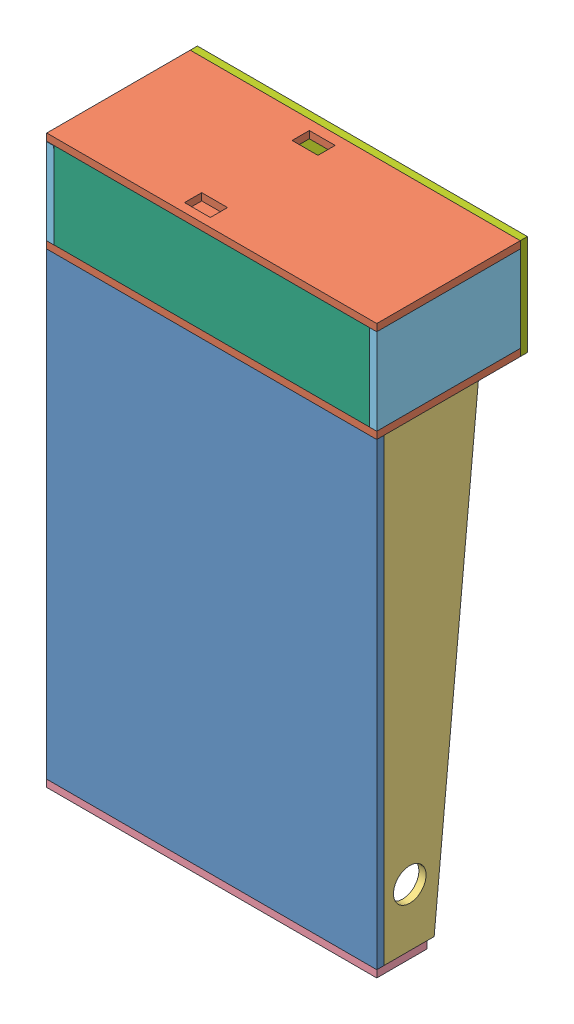
SolidWorks assembly pinball enclosure, configuration Default. Lengths in mm.
Overall size (292.1 501.65 133.49).
10 component instances, 7 part files, 20 mates.
Components (placement in the parent):
- base-1: base [Default] at (-22.2042 13.1183 317.2401) size (292.1 406.4 6.35)
- backboard-1: backboard [Default] at (-22.2042 425.8683 196.5901) x (1 0 0) z (0 -1 0) size (292.1 127 6.35)
- side panel-1: side panel [Default] at (263.5458 419.5183 317.2401) x (0 -1 0) z (1 0 0) size (406.4 83.57 6.35)
- side panel-2: side panel [Default] at (-22.2042 419.5183 317.2401) x (0 -1 0) z (1 0 0) size (406.4 83.57 6.35)
- front panel-1: front panel [Default] at (-22.2042 6.7683 323.5901) x (1 0 0) z (0 1 0) size (292.1 57.15 6.35)
- backboard side panel-1: backboard side panel [Default] at (263.5458 502.0683 323.5901) x (0 -1 0) z (1 0 0) size (76.2 127 6.35)
- backboard base-1: backboard base [Default] at (-15.8542 425.8683 317.2401) size (279.4 76.2 6.35)
- backboard-2: backboard [Default] at (-22.2042 508.4183 196.5901) x (1 0 0) z (0 -1 0) size (292.1 127 6.35)
- backboard top-1: backboard top [Default] at (-22.2042 419.5183 190.2401) size (292.1 88.9 6.35)
- backboard side panel-3: backboard side panel [Default] at (-15.8542 425.6263 323.5898) x (0 0.999998 0.001905) z (-1 0 0) size (76.2 127 6.35)
Mates (geometry in assembly coordinates):
- Coincident1: coincident anti-aligned: line of base-1 through (269.8958 419.5183 323.5901) axis (-1 0 0); line of backboard-1 through (-22.2042 419.5183 323.5901) axis (1 0 0)
- Coincident2: coincident anti-aligned: plane of base-1 through (-22.2042 419.5183 323.5901) normal (0 1 0); plane of backboard-1 through (-22.2042 419.5183 196.5901) normal (0 -1 0)
- Coincident3: coincident anti-aligned: line of base-1 through (-22.2042 419.5183 323.5901) axis (0 0 -1); line of backboard-1 through (-22.2042 419.5183 196.5901) axis (0 0 1)
- Coincident17: coincident: point of base-1; point of side panel-1
- Coincident18: coincident aligned: line of base-1 through (269.8958 13.1183 323.5901) axis (0 0 -1); line of side panel-1 through (269.8958 13.1183 317.2401) axis (0 0 -1)
- Coincident19: coincident: point of base-1; point of side panel-2
- Coincident20: coincident aligned: line of base-1 through (-22.2042 13.1183 323.5901) axis (0 0 -1); line of side panel-2 through (-22.2042 13.1183 317.2401) axis (0 0 -1)
- Coincident21: coincident: point of base-1; point of front panel-1
- Coincident22: coincident: point of base-1; point of front panel-1
- Coincident23: coincident: line of side panel-2 through (-22.2042 13.1183 317.2401) axis (0 0 -1); point of front panel-1
- Coincident24: coincident: point of base-1; point of front panel-1
- Coincident26: coincident anti-aligned: line of backboard-1 through (269.8958 425.8683 196.5901) axis (0 0 1); line of backboard side panel-1 through (269.8958 425.8683 323.5901) axis (0 0 -1)
- Coincident27: coincident: point of backboard-1; point of backboard side panel-1
- Coincident28: coincident anti-aligned: line of backboard-1 through (269.8958 419.5183 323.5901) axis (0 1 0); line of backboard side panel-1 through (269.8958 502.0683 323.5901) axis (0 -1 0)
- Parallel3: parallel anti-aligned: plane of backboard-1 through (-22.2042 425.8683 196.5901) normal (0 1 0); plane of backboard base-1 through (-15.8542 425.8683 323.5901) normal (0 -1 0)
- Coincident37: coincident: line of backboard side panel-1 through (263.5458 502.0683 196.5901) axis (0 0 1); point of backboard base-1
- Coincident38: coincident: point of backboard-1; point of backboard top-1
- Coincident39: coincident: point of backboard-2; point of backboard top-1
- Coincident44: coincident anti-aligned: line of backboard side panel-1 through (263.5458 502.0683 323.5901) axis (0 -1 0); line of backboard base-1 through (263.5458 425.8683 323.5901) axis (0 1 0)
- Coincident50: coincident: point of backboard-1; point of backboard side panel-3
